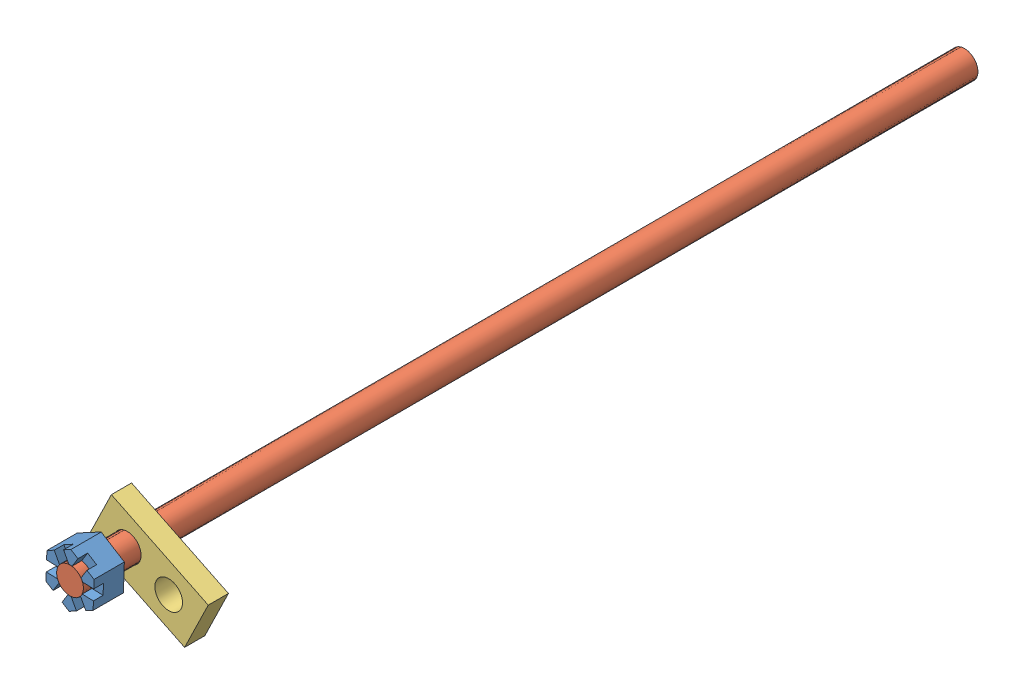
SolidWorks assembly RouseTech_Motor_Retainer_Rod_Asm, configuration Default. Lengths in mm.
Overall size (28.4 22.55 210.82).
3 component instances, 3 part files, 4 mates.
Components (placement in the parent):
- 0.25in-20_Wired_Nut_MC-91853A029-1: 0.25in-20_Wired_Nut_MC-91853A029 [Default] at (-6.1943 1.0961 -1.0479) size (11.31 12.82 7.14)
- 025in_Threaded_Rod-1: 025in_Threaded_Rod [Default] at (-6.1943 1.0961 -204.7242) size (6.35 6.35 210.82)
- 0.25_Threaded_Rod_Hold_Plates-1: 0.25_Threaded_Rod_Hold_Plates [Default] at (-1.3093 -1.2878 -12.1604) x (0.898698 -0.438568 0) z (0 0 1) size (25.4 12.7 4.76)
Mates (geometry in assembly coordinates):
- Coincident1: coincident aligned: axis of 0.25in-20_Wired_Nut_MC-91853A029-1 through (-6.1943 1.0961 6.0958) axis (0 0 -1); axis of 025in_Threaded_Rod-1 through (-6.1943 1.0961 6.0958) axis (0 0 -1)
- Coincident2: coincident aligned: plane of 0.25in-20_Wired_Nut_MC-91853A029-1 through (-0.5371 4.1224 6.0958) normal (0 0 1); plane of 025in_Threaded_Rod-1 through (-6.1943 1.0961 6.0958) normal (0 0 1)
- Coincident3: coincident anti-aligned: axis of 025in_Threaded_Rod-1 through (-6.1943 1.0961 6.0958) axis (0 0 -1); axis of 0.25_Threaded_Rod_Hold_Plates-1 through (-6.1943 1.0961 -12.1604) axis (0 0 1)
- Distance1: distance = 6.35 mm anti-aligned: plane of 0.25_Threaded_Rod_Hold_Plates-1 through (-9.9379 9.9888 -7.3979) normal (0 0 1); plane of 0.25in-20_Wired_Nut_MC-91853A029-1 through (-0.5371 4.1224 -1.0479) normal (0 0 -1)
